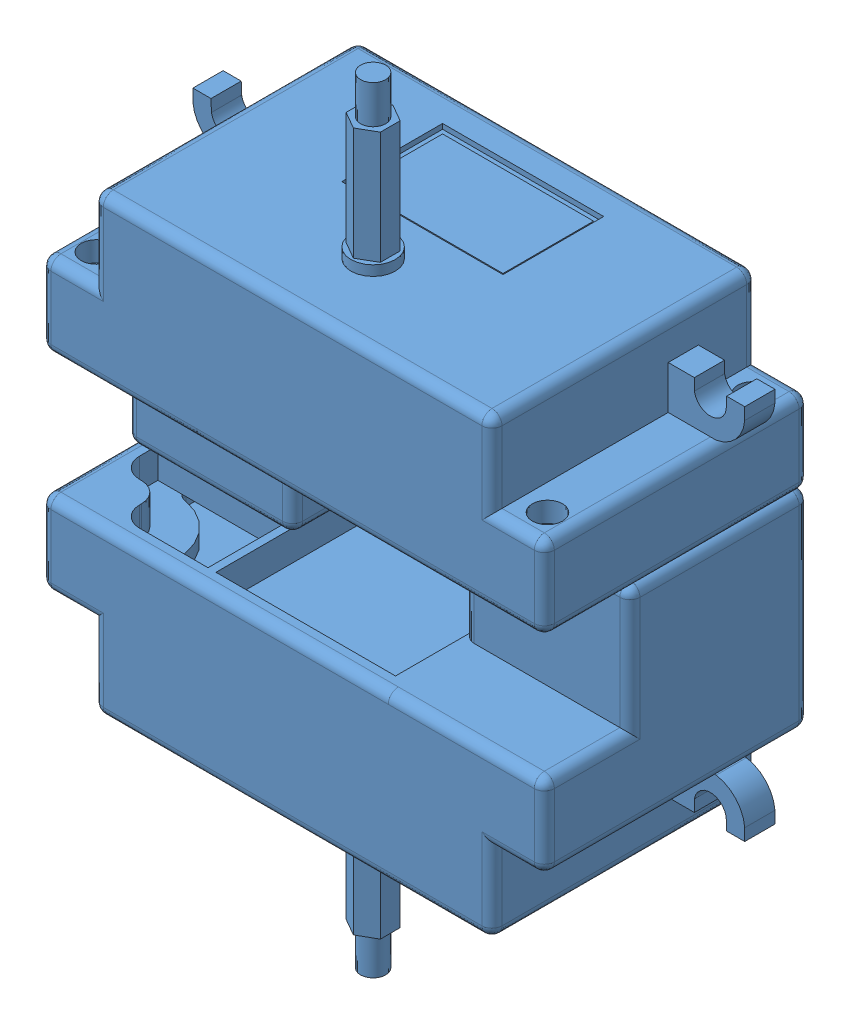
SolidWorks assembly 2GMR, configuration Défaut. Lengths in mm.
Overall size (54.8 77 26.3).
2 component instances, 1 part files, 3 mates.
Components (placement in the parent):
- 1GMP-2: 1GMP [Défaut] at (-0.1859 15.6142 -13.8438) size (54.8 46.6 26.3)
- 1GMP-3: 1GMP [Défaut] at (-0.1859 15.6142 -13.8438) x (-1 0 0) z (0 0 1) size (54.8 46.6 26.3)
Mates (geometry in assembly coordinates):
- Coïncidente1: coincident anti-aligned: plane of 1GMP-2; plane of 1GMP-3
- Coïncidente2: coincident aligned: plane of 1GMP-2; plane of 1GMP-3
- Coïncidente3: coincident aligned: plane of 1GMP-2; plane of 1GMP-3
